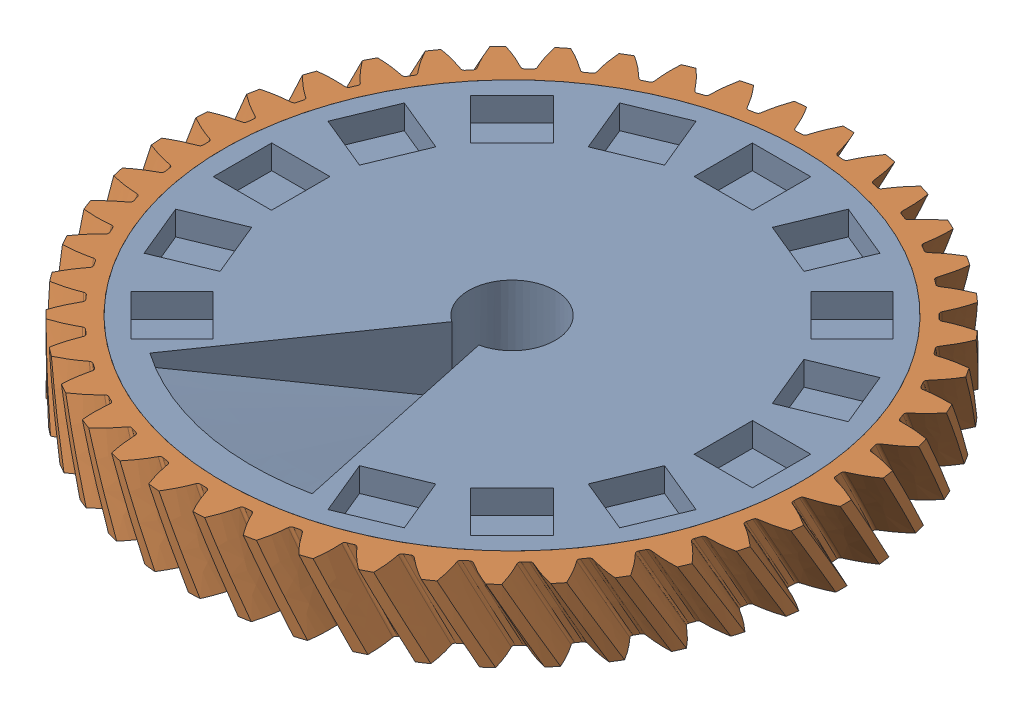
SolidWorks assembly finalCarouselSummer, configuration Default. Lengths in mm.
Overall size (137.18 41.6 137.16).
2 component instances, 2 part files, 3 mates.
Components (placement in the parent):
- carousel 2.0-1: carousel 2.0 [Default] at (-220.7226 -7.0943 -99.6764) size (120 41.6 120)
- FINISHED_outergear-1: FINISHED_outergear [Default] at (-220.7226 -7.0943 -99.6764) size (137.18 15.01 137.16)
Mates (geometry in assembly coordinates):
- Concentric1: concentric aligned: cylinder of carousel 2.0-1 through (-220.7226 -7.0943 -99.6764) axis (0 -1 0) radius 60; cylinder of FINISHED_outergear-1 through (-220.7226 22.9057 -99.6764) axis (0 -1 0) radius 60
- Concentric4: concentric anti-aligned: circle of carousel 2.0-1; circle of FINISHED_outergear-1
- Coincident1: coincident anti-aligned: circle of carousel 2.0-1; circle of FINISHED_outergear-1
